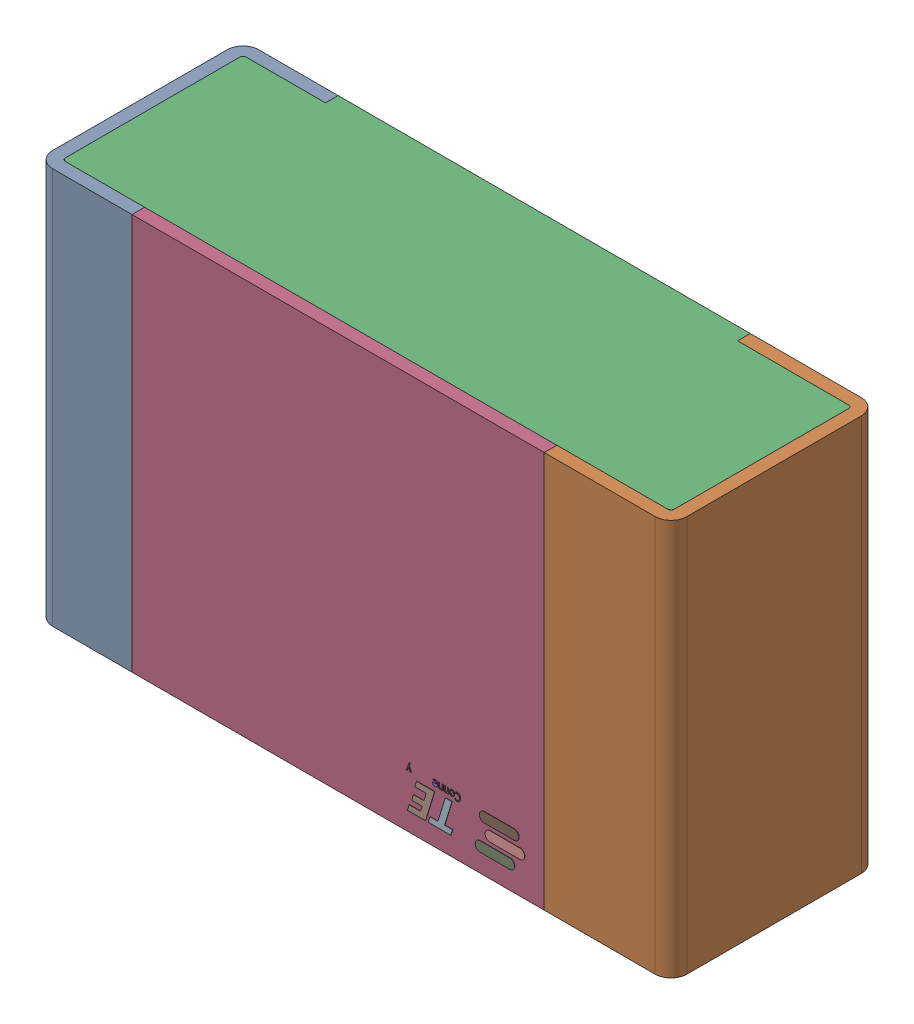
SolidWorks assembly RLH3.step, configuration Default. Lengths in mm.
Overall size (2 1.25 0.65).
5 component instances, 4 part files, 0 mates.
Components (placement in the parent):
- Res_TE_Connectivity_CPF0805B66R5E1_eec.step-1: Res_TE_Connectivity_CPF0805B66R5E1_eec.step [Default] at (5.191 17.272 0) x (-1 0 0) z (0 0 1) size (2 1.25 0.65)
  - 1.step-1: 1.step [Default] at origin size (2 1.25 0.65)
  - 2.step-1: 2.step [Default] at origin size (1.92 1.25 0.61)
  - 3.step-1: 3.step [Default] at origin size (1.3 1.25 0.04)
  - TE connectivity Logo 1 (2).step-1: TE connectivity Logo 1 (2).step [Default] at (5.4285 0.313 0.551) x (-1 0 0) z (0 0 1) size (0.37 0.13 0.11)
